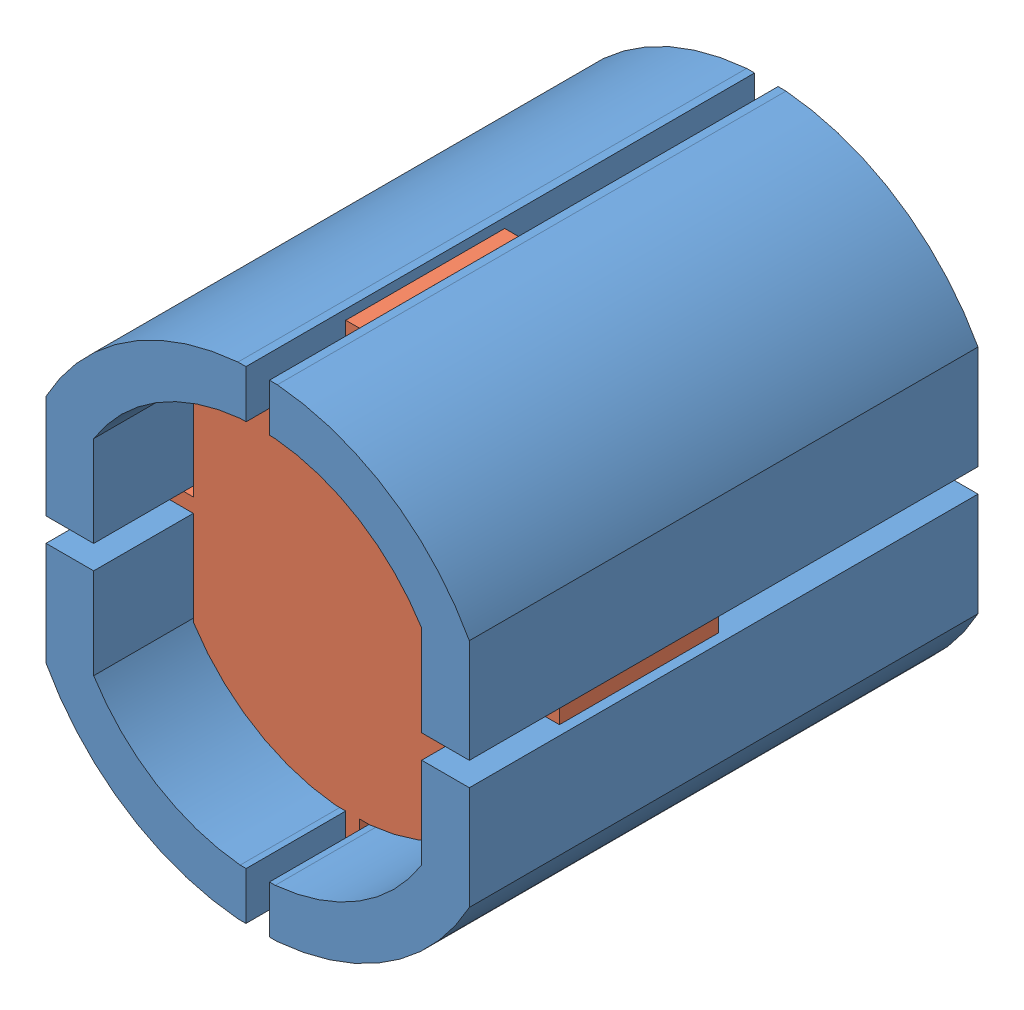
SolidWorks assembly modellingFemaleConnector, configuration Default. Lengths in mm.
Overall size (26.63 30.34 32).
2 component instances, 2 part files, 3 mates.
Components (placement in the parent):
- t150 hub side-1: t150 hub side [Default] at (25.6547 16.335 17.5757) size (26.63 30.34 32)
- female-1: female [Default] at (13.077 16.335 33.6083) size (26.03 29.74 10)
Mates (geometry in assembly coordinates):
- Parallel3: parallel aligned: line of t150 hub side-1 through (27.1336 43.6737 49.5757) axis (0 1 0); line of female-1 through (26.8332 43.3737 43.6083) axis (0 1 0)
- Distance4: distance = 0.3 mm: line of female-1 through (36.4102 31.0584 43.6083) axis (1 0 0); plane of t150 hub side-1 through (36.7102 30.7584 68.7211) normal (0 1 0)
- Distance5: distance = 0.3 mm: line of female-1 through (25.967 19.3338 43.6083) axis (-0.0041 -0.999992 0); plane of t150 hub side-1 through (25.6547 16.335 68.7211) normal (0.999992 -0.0041 0)
